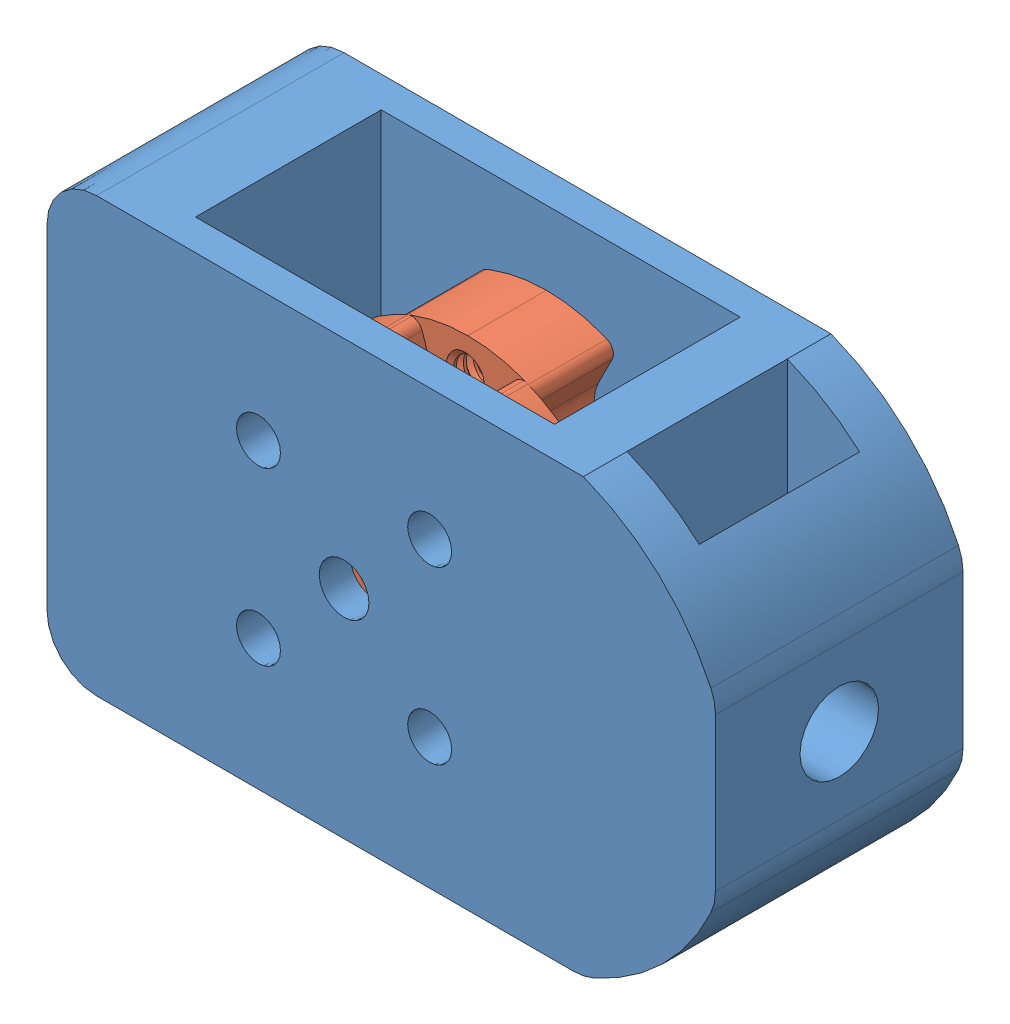
SolidWorks assembly ARMUS-REV4-200, configuration Défaut. Lengths in mm.
Overall size (54 35 20).
3 component instances, 3 part files, 9 mates.
Components (placement in the parent):
- ARMUS-REV4-201-1: ARMUS-REV4-201 [Défaut] at origin size (54 35 20)
- HUB-0_25-1: HUB-0_25 [Défaut] at (-30.0172 37.5992 -6.2696) x (-1 0 0) z (0 -1 0) size (25.4 12.7 25.4)
- hex nut_ai-3: hex nut_ai [HNUT 0.2500-20-D-N] at (19.3798 17.5 0) x (0 0.5 0.866025) z (-1 0 0) (suppressed, hidden)
Mates (geometry in assembly coordinates):
- Coïncidente1: coordinate: point of ARMUS-REV2-003-1
- Largeur2: width anti-aligned: plane of ARMUS-REV2-003-1 through (14.5 0 7.5) normal (0 0 -1); plane of HUB-0_25-1 through (14.5 0 -7.5) normal (0 0 1); plane of ARMUS-REV2-003-1 through (0 17.5 6.35) normal (0 0 1); plane of HUB-0_25-1 through (0 17.5 -6.35) normal (0 0 -1)
- Largeur3: width aligned: plane of ARMUS-REV2-003-1 through (0 35 0) normal (0 1 0); plane of HNUT 0.2500-20-D-N-1 through (0 0 0) normal (0 -1 0); plane of ARMUS-REV2-003-1 through (25.1202 23.0562 3.2079) normal (0 1 0); plane of HNUT 0.2500-20-D-N-1 through (25.1202 11.9437 -3.2079) normal (0 -1 0)
- Largeur4: width: cylinder of ARMUS-REV2-003-1; plane of HNUT 0.2500-20-D-N-1 through (30 35 10) normal (0 0 1); cylinder of ARMUS-REV2-003-1 through (25.1202 17.5 0) axis (-1 0 0) radius 2.5527
- Largeur5: width aligned: plane of ARMUS-REV2-003-1 through (14.5 0 7.5) normal (-1 0 0); plane of HNUT 0.2500-20-D-N-1 through (30 35 10) normal (1 0 0); plane of ARMUS-REV2-003-1 through (19.3798 23.0562 -3.2079) normal (-1 0 0); plane of HNUT 0.2500-20-D-N-1 through (25.1202 23.0562 -3.2079) normal (1 0 0)
- Largeur6: width aligned: plane of ARMUS-REV2-003-1 through (14.5 0 -7.5) normal (0 0 1); plane of ARMUS-REV2-003-1 through (14.5 0 7.5) normal (0 0 -1); plane of HUB-0_25-1 through (0 17.5 6.35) normal (0 0 1); plane of HUB-0_25-1 through (0 17.5 -6.35) normal (0 0 -1)
- Largeur7: width: plane of ARMUS-REV2-003-1 through (14.5 0 7.5) normal (-1 0 0); plane of ARMUS-REV2-003-1 through (-14.5 0 7.5) normal (1 0 0); cylinder of HUB-0_25-1 through (0 17.5 1.5875) axis (0 0 1) radius 3.175
- Parallèle1: parallel anti-aligned: plane of HUB-0_25-1 through (-30.0172 37.5992 -6.2696) normal (-1 0 0)
- Largeur8: width: plane of ARMUS-REV2-003-1 through (0 0 0) normal (0 -1 0); plane of HUB-0_25-1 through (0 35 0) normal (0 1 0); cylinder of ARMUS-REV2-003-1 through (0 17.5 1.5875) axis (0 0 1) radius 3.175
